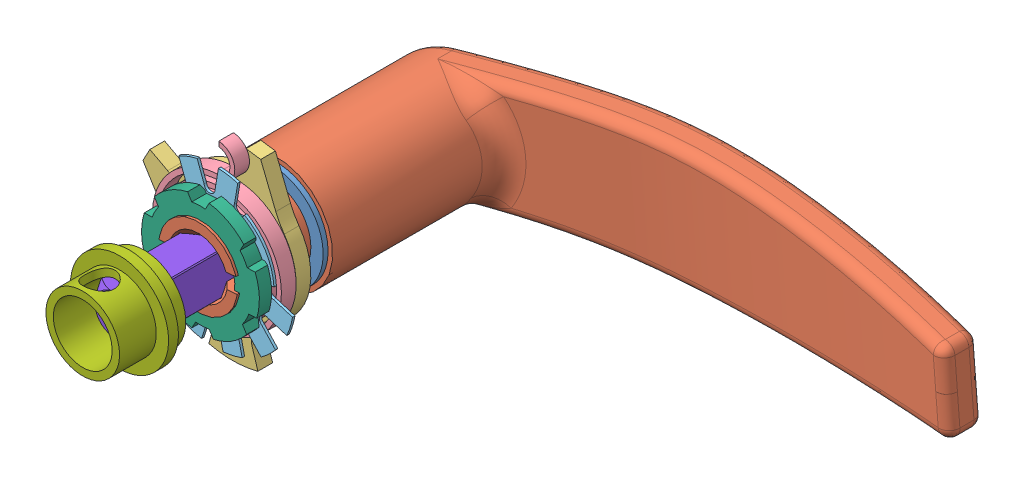
SolidWorks assembly poignee exterieure, configuration Défaut. Lengths in mm.
Overall size (128.25 51.13 93.38).
10 component instances, 8 part files, 18 mates.
Components (placement in the parent):
- pièce a3-1: pièce a3 [Défaut] at (-71.1604 -5.4234 -28.5) x (-1 0 0) z (0 0 -1) size (21 21 1)
- pièce a3-2: pièce a3 [Défaut] at (-71.1604 -5.4234 -28.5) x (-0.978032 -0.208453 0) z (0 0 1) size (21 21 1)
- pièce a3-3: pièce a3 [Défaut] at (-71.1604 -5.4234 -33.5) x (0.888915 -0.458071 0) z (0 0 1) size (21 21 1)
- bequille-1: bequille [Défaut] at (-71.0971 -5.4183 -34) x (-0.081007 0.996714 0) z (0 0 1) size (41.55 120 69.88)
- pièce a16-1: pièce a16 [Défaut] at (-71.1604 -5.4234 -25) x (-0.999944 -0.010542 0) z (0 0 -1) size (31.16 38.76 3.06)
- pièce a5-1: pièce a5 [Défaut] at (-70.822 -5.1825 -23.5) x (-0.082996 -0.99655 0) z (0 0 -1) size (33.22 26.47 3.09)
- pièce a7-1: pièce a7 [Défaut] at (-71.1604 -5.4234 -21.5) x (-0.986222 0.165429 0) z (0 0 -1) size (28 32 0.5)
- pièce a4-1: pièce a4 [Défaut] at (-71.1604 -5.4234 -18.5) x (-0.884093 0.467311 0) z (0 0 -1) size (23.6 24 3)
- Pièce16-1: Pièce16 [Défaut] at (-71.1604 -5.4234 -7) x (0 0 1) z (0.996714 0.081007 0) size (12.5 20 20)
- carre-1: carre [Défaut] at (-71.1604 -5.4234 -53) x (-0.996714 -0.081007 0) z (0 0 -1) size (8 8 52)
Mates (geometry in assembly coordinates):
- Coïncidente327: coincident aligned: plane of pièce a3-1 through (-71.1604 -5.4234 -28) normal (0 0 1); plane of pièce a3-2 through (-71.1604 -5.4234 -28) normal (0 0 1)
- Coïncidente328: coincident anti-aligned: plane of pièce a3-2 through (-71.1604 -5.4234 -28) normal (0 0 1); plane of pièce a16-1 through (-71.1604 -5.4234 -28) normal (0 0 -1)
- Coïncidente331: coincident anti-aligned: plane of pièce a3-3 through (-71.1604 -5.4234 -34) normal (0 0 -1); plane of bequille-1 through (-71.1604 -5.4234 -34) normal (0 0 1)
- Coaxiale20: concentric anti-aligned: cylinder of pièce a16-1 through (-71.1604 -5.4234 -28) axis (0 0 1) radius 8; cylinder of bequille-1 through (-71.1604 -5.4234 -18) axis (0 0 -1) radius 8
- Tangent5: tangent: face of pièce a5-1; cylinder of bequille-1 through (-71.1604 -5.4234 -18) axis (0 0 -1) radius 8
- Coïncidente13: coincident anti-aligned: plane of pièce a16-1 through (-71.1604 -5.4234 -25) normal (0 0 1); plane of pièce a5-1 through (-63.1763 -5.8193 -25) normal (0 0 -1)
- Coïncidente50: coincident anti-aligned: plane of pièce a16-1 through (-71.1604 -5.4234 -25) normal (0 0 1); plane of pièce a5-1 through (-63.1763 -5.8193 -25) normal (0 0 -1)
- Coïncidente305: coincident anti-aligned: plane of pièce a4-1 through (-71.1604 -5.4234 -21.5) normal (0 0 -1); plane of pièce a7-1 through (-72.3014 6.4687 -21.5) normal (0 0 1)
- Coaxiale110: concentric anti-aligned: cylinder of pièce a7-1 through (-71.1604 -5.4234 -22) axis (0 0 1) radius 8; cylinder of bequille-1 through (-71.1604 -5.4234 -18) axis (0 0 -1) radius 8
- Coïncidente303: coincident anti-aligned: plane of pièce a7-1 through (-79.1142 -4.5649 -22) normal (-0.081007 0.996714 0); plane of bequille-1 through (-91.2161 -5.5485 -30) normal (0.081007 -0.996714 0)
- Coïncidente302: coincident anti-aligned: plane of pièce a5-1 through (-62.1797 -5.9023 -22) normal (0 0 1); plane of pièce a7-1 through (-72.3014 6.4687 -22) normal (0 0 -1)
- Coaxiale103: concentric aligned: cylinder of pièce a4-1 through (-71.1604 -5.4234 -21.5) axis (0 0 -1) radius 7; cylinder of bequille-1 through (-71.1604 -5.4234 -18) axis (0 0 -1) radius 8
- Coïncidente332: coincident anti-aligned: plane of bequille-1 through (-74.8232 -9.7343 -53) normal (0.996714 0.081007 0); plane of carre-1 through (-75.4712 -1.7606 -1) normal (-0.996714 -0.081007 0)
- Coïncidente333: coincident anti-aligned: plane of bequille-1 through (-75.4712 -1.7606 -53) normal (0.081007 -0.996714 0); plane of carre-1 through (-67.4975 -1.1126 -1) normal (-0.081007 0.996714 0)
- Coïncidente334: coincident anti-aligned: plane of bequille-1 through (-74.8232 -9.7343 -53) normal (0 0 1); plane of carre-1 through (-66.8495 -9.0863 -53) normal (0 0 -1)
- Coïncidente339: coincident: plane of Pièce16-1 through (-75.4712 -1.7606 5.5) normal (0.081007 -0.996714 0); plane of carre-1 through (-67.4975 -1.1126 -1) normal (-0.081007 0.996714 0)
- Coïncidente340: coincident: plane of Pièce16-1 through (-74.8232 -9.7343 5.5) normal (0.996714 0.081007 0); plane of carre-1 through (-75.4712 -1.7606 -1) normal (-0.996714 -0.081007 0)
- Coïncidente341: coincident aligned: plane of Pièce16-1 through (-71.1604 -5.4234 -7) normal (0 0 -1); plane of carre-1 through (-71.1604 -5.4234 -7) normal (0 0 -1)
